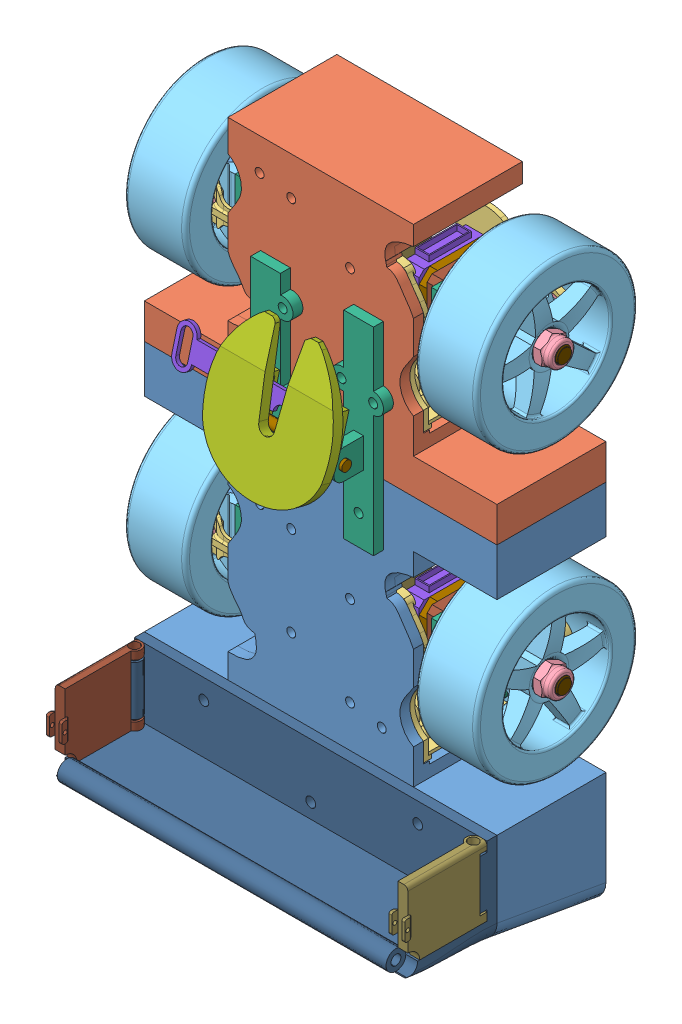
SolidWorks assembly Chassis assembly 2 - kopie, configuration Default. Lengths in mm.
Overall size (185.37 311.7 137.75).
160 component instances, 31 part files, 29 mates.
Components (placement in the parent):
- Dolly chassis half 1-1: Dolly chassis half 1 [Default] at (2.6348 264.5467 189.9496) size (178 185.23 55)
- Dolly chassis half 2-1: Dolly chassis half 2 [Default] at (2.6348 264.5467 189.9496) size (178 119.07 55)
- Module Assembly-1: Module Assembly [Default] at (-63.8652 93.3967 162.4496) x (0 -1 0) z (-1 0 0) size (68.25 51.28 97.81)
  - Housing-1: Housing [Default] at origin size (64.25 48.5 67.91)
  - Bearing 12x8-1: Bearing 12x8 [Default] at (0 -18.25 0.75) x (-0.914388 0 0.40484) z (-0.40484 0 -0.914388) size (12 3.5 12)
  - Spindle-1: Spindle [Default] at (0 2 0.75) size (49.04 45 20.5)
  - Spindle base-1: Spindle base [Default] at (0 2 -15.25) x (-1 0 0) z (0 -1 0) size (37.62 3.5 44.8)
  - Encoder-1: Encoder [Défaut] at (0 2 -12.48) x (0 1 0) z (0 0 1) size (28.68 37.25 10.4)
  - Wheel-1: Wheel [Default] at (0 2 -8.55) x (0.929787 0.368098 0) z (0.368098 -0.929787 0) size (81.5 31 81.5) (hidden)
  - Stepper Nema14-1: Stepper Nema14 [Predeterminado] at (4.764 -15.5 -30.1157) x (-1 0 0) z (0 1 0) size (37.8 40 35)
    - nema14_base-1: nema14_base [Predeterminado] at (-12.736 -8.6343 35) size (37.8 9 35)
    - nema14_centro-1: nema14_centro [Predeterminado] at (-12.736 0.3657 35) size (35 4 35)
    - nema14_eje-1: nema14_eje [Predeterminado] at (4.764 -6.6343 17.5) x (0 1 0) z (-0.939004 0 0.343907) size (38 5 5)
    - nema14_techo-1: nema14_techo [Predeterminado] at (-12.736 4.3657 35) size (35 9 35)
  - Servo motor-1: Servo motor [Default] at (-25.7048 26.288 -66.0832) x (0 0 1) z (1 0 0) size (11.5 29.2 32.5) (flexible)
    - TowerPro-SG90-Body-1: TowerPro-SG90-Body [Default] at (13.6721 7.288 30.7048) size (11.5 26 32.5)
    - ServoFinalGear-1: ServoFinalGear [Default] at (13.6721 33.288 25.7048) x (0.607544 0 -0.794286) z (0.794286 0 0.607544) size (4.64 3.2 4.64)
  - Control arm-1: Control arm [Default] at (0 -7.5 -52.4111) x (0.891007 0 0.45399) z (0.45399 0 -0.891007) size (37.9 4.5 7.8)
  - Ball joint assy-1: Ball joint assy [Default] at (-26.7302 -5 -12.8697) x (-0.874356 0 0.485286) z (0.485286 0 0.874356) size (15.43 16.21 22.24) (flexible)
    - Ball-1: Ball [Default] at origin size (5.5 15.11 5.5)
    - Joint-1: Joint [Default] at (-3.8823 13.66 -6.9948) x (0.874356 0 -0.485286) z (0 -1 0) size (5.1 22.6 5.1)
  - Ball joint assy-2: Ball joint assy [Default] at (-26.7302 -5 -66.0308) x (-0.846813 0 0.531891) z (0.531891 0 0.846813) size (16.34 16.21 21.85) (flexible)
    - Ball-1: Ball [Default] at origin size (5.5 15.11 5.5)
    - Joint-1: Joint [Default] at (4.2551 13.66 6.7745) x (-0.846813 0 0.531891) z (0 -1 0) size (5.1 22.6 5.1)
  - Steering rod-1: Steering rod [Default] at (-26.7302 -18.66 -18.4608) x (-0.014502 0.999895 0) z (-0.999895 -0.014502 0) size (3 28.27 3)
  - Wheel adapter-1: Wheel adapter [Default] at (0 2 -13.8175) x (0.291296 -0.956633 0) z (-0.956633 -0.291296 0) size (8.34 40 8.37)
  - Wheel spacer-1: Wheel spacer [Default] at (0 2 12.25) x (0.368098 -0.929787 0) z (0.929787 0.368098 0) size (13.86 8 12)
  - M3x5 din 7984-1: M3x5 din 7984 [Default] at (15.31 20.9 -16.25) x (0.933505 0.358563 0) z (0 0 -1) size (5.5 5.5 7)
  - Housing lid-1: Housing lid [Default] at (0 4 0) x (-1 0 0) z (0 0 1) size (68.25 9.28 69.91)
  - Bearing 12x8-3: Bearing 12x8 [Default] at (0 22.25 0.75) x (-0.914388 0 0.40484) z (0.40484 0 0.914388) size (12 3.5 12)
  - M8 nut-1: M8 nut [Default] at (0 2 16.6825) x (-0.817347 -0.576146 0) z (0 0 1) size (13 16.06 8.5)
  - M3x5 din 7984-2: M3x5 din 7984 [Default] at (15.31 -16.9 -16.25) x (-0.933505 0.358563 0) z (0 0 -1) size (5.5 5.5 7)
  - M3x5 din 7984-3: M3x5 din 7984 [Default] at (-15.31 20.9 -16.25) x (0.933505 -0.358563 0) z (0 0 -1) size (5.5 5.5 7)
  - M3x5 din 7984-4: M3x5 din 7984 [Default] at (-15.31 -16.9 -16.25) x (-0.933505 -0.358563 0) z (0 0 -1) size (5.5 5.5 7)
  - M3x5 din 7984-5: M3x5 din 7984 [Default] at (-13 15 -17.75) x (0.999849 0.017374 0) z (0 0 1) size (5.5 5.5 7)
  - M3x5 din 7984-6: M3x5 din 7984 [Default] at (-13 -11 -17.75) x (-0.999849 0.017374 0) z (0 0 1) size (5.5 5.5 7)
  - M3x5 din 7984-7: M3x5 din 7984 [Default] at (13 15 -17.75) x (0.999849 -0.017374 0) z (0 0 1) size (5.5 5.5 7)
  - M3x5 din 7984-8: M3x5 din 7984 [Default] at (13 -11 -17.75) x (-0.999849 -0.017374 0) z (0 0 1) size (5.5 5.5 7)
- Module Assembly-2: Module Assembly [Default] at (69.1348 93.3967 162.4496) x (0 1 0) z (1 0 0) size (68.25 51.28 97.81)
  - Housing-1: Housing [Default] at origin size (64.25 48.5 67.91)
  - Bearing 12x8-1: Bearing 12x8 [Default] at (0 -18.25 0.75) x (-0.914388 0 0.40484) z (-0.40484 0 -0.914388) size (12 3.5 12)
  - Spindle-1: Spindle [Default] at (0 2 0.75) size (49.04 45 20.5)
  - Spindle base-1: Spindle base [Default] at (0 2 -15.25) x (-1 0 0) z (0 -1 0) size (37.62 3.5 44.8)
  - Encoder-1: Encoder [Défaut] at (0 2 -12.48) x (0 1 0) z (0 0 1) size (28.68 37.25 10.4)
  - Wheel-1: Wheel [Default] at (0 2 -8.55) x (0.929787 0.368098 0) z (0.368098 -0.929787 0) size (81.5 31 81.5) (hidden)
  - Stepper Nema14-1: Stepper Nema14 [Predeterminado] at (4.764 -15.5 -30.1157) x (-1 0 0) z (0 1 0) size (37.8 40 35)
    - nema14_base-1: nema14_base [Predeterminado] at (-12.736 -8.6343 35) size (37.8 9 35)
    - nema14_centro-1: nema14_centro [Predeterminado] at (-12.736 0.3657 35) size (35 4 35)
    - nema14_eje-1: nema14_eje [Predeterminado] at (4.764 -6.6343 17.5) x (0 1 0) z (-0.939004 0 0.343907) size (38 5 5)
    - nema14_techo-1: nema14_techo [Predeterminado] at (-12.736 4.3657 35) size (35 9 35)
  - Servo motor-1: Servo motor [Default] at (-25.7048 26.288 -66.0832) x (0 0 1) z (1 0 0) size (11.5 29.2 32.5) (flexible)
    - TowerPro-SG90-Body-1: TowerPro-SG90-Body [Default] at (13.6721 7.288 30.7048) size (11.5 26 32.5)
    - ServoFinalGear-1: ServoFinalGear [Default] at (13.6721 33.288 25.7048) x (0.607544 0 -0.794286) z (0.794286 0 0.607544) size (4.64 3.2 4.64)
  - Control arm-1: Control arm [Default] at (0 -7.5 -52.4111) x (0.891007 0 0.45399) z (0.45399 0 -0.891007) size (37.9 4.5 7.8)
  - Ball joint assy-1: Ball joint assy [Default] at (-26.7302 -5 -12.8697) x (-0.874356 0 0.485286) z (0.485286 0 0.874356) size (15.43 16.21 22.24) (flexible)
    - Ball-1: Ball [Default] at origin size (5.5 15.11 5.5)
    - Joint-1: Joint [Default] at (-3.8823 13.66 -6.9948) x (0.874356 0 -0.485286) z (0 -1 0) size (5.1 22.6 5.1)
  - Ball joint assy-2: Ball joint assy [Default] at (-26.7302 -5 -66.0308) x (-0.846813 0 0.531891) z (0.531891 0 0.846813) size (16.34 16.21 21.85) (flexible)
    - Ball-1: Ball [Default] at origin size (5.5 15.11 5.5)
    - Joint-1: Joint [Default] at (4.2551 13.66 6.7745) x (-0.846813 0 0.531891) z (0 -1 0) size (5.1 22.6 5.1)
  - Steering rod-1: Steering rod [Default] at (-26.7302 -18.66 -18.4608) x (-0.014502 0.999895 0) z (-0.999895 -0.014502 0) size (3 28.27 3)
  - Wheel adapter-1: Wheel adapter [Default] at (0 2 -13.8175) x (0.291296 -0.956633 0) z (-0.956633 -0.291296 0) size (8.34 40 8.37)
  - Wheel spacer-1: Wheel spacer [Default] at (0 2 12.25) x (0.368098 -0.929787 0) z (0.929787 0.368098 0) size (13.86 8 12)
  - M3x5 din 7984-1: M3x5 din 7984 [Default] at (15.31 20.9 -16.25) x (0.933505 0.358563 0) z (0 0 -1) size (5.5 5.5 7)
  - Housing lid-1: Housing lid [Default] at (0 4 0) x (-1 0 0) z (0 0 1) size (68.25 9.28 69.91)
  - Bearing 12x8-3: Bearing 12x8 [Default] at (0 22.25 0.75) x (-0.914388 0 0.40484) z (0.40484 0 0.914388) size (12 3.5 12)
  - M8 nut-1: M8 nut [Default] at (0 2 16.6825) x (-0.817347 -0.576146 0) z (0 0 1) size (13 16.06 8.5)
  - M3x5 din 7984-2: M3x5 din 7984 [Default] at (15.31 -16.9 -16.25) x (-0.933505 0.358563 0) z (0 0 -1) size (5.5 5.5 7)
  - M3x5 din 7984-3: M3x5 din 7984 [Default] at (-15.31 20.9 -16.25) x (0.933505 -0.358563 0) z (0 0 -1) size (5.5 5.5 7)
  - M3x5 din 7984-4: M3x5 din 7984 [Default] at (-15.31 -16.9 -16.25) x (-0.933505 -0.358563 0) z (0 0 -1) size (5.5 5.5 7)
  - M3x5 din 7984-5: M3x5 din 7984 [Default] at (-13 15 -17.75) x (0.999849 0.017374 0) z (0 0 1) size (5.5 5.5 7)
  - M3x5 din 7984-6: M3x5 din 7984 [Default] at (-13 -11 -17.75) x (-0.999849 0.017374 0) z (0 0 1) size (5.5 5.5 7)
  - M3x5 din 7984-7: M3x5 din 7984 [Default] at (13 15 -17.75) x (0.999849 -0.017374 0) z (0 0 1) size (5.5 5.5 7)
  - M3x5 din 7984-8: M3x5 din 7984 [Default] at (13 -11 -17.75) x (-0.999849 -0.017374 0) z (0 0 1) size (5.5 5.5 7)
- Module Assembly-3: Module Assembly [Default] at (69.1348 238.0467 162.4496) x (0 1 0) z (1 0 0) size (68.25 51.28 97.81)
  - Housing-1: Housing [Default] at origin size (64.25 48.5 67.91)
  - Bearing 12x8-1: Bearing 12x8 [Default] at (0 -18.25 0.75) x (-0.914388 0 0.40484) z (-0.40484 0 -0.914388) size (12 3.5 12)
  - Spindle-1: Spindle [Default] at (0 2 0.75) size (49.04 45 20.5)
  - Spindle base-1: Spindle base [Default] at (0 2 -15.25) x (-1 0 0) z (0 -1 0) size (37.62 3.5 44.8)
  - Encoder-1: Encoder [Défaut] at (0 2 -12.48) x (0 1 0) z (0 0 1) size (28.68 37.25 10.4)
  - Wheel-1: Wheel [Default] at (0 2 -8.55) x (0.929787 0.368098 0) z (0.368098 -0.929787 0) size (81.5 31 81.5) (hidden)
  - Stepper Nema14-1: Stepper Nema14 [Predeterminado] at (4.764 -15.5 -30.1157) x (-1 0 0) z (0 1 0) size (37.8 40 35)
    - nema14_base-1: nema14_base [Predeterminado] at (-12.736 -8.6343 35) size (37.8 9 35)
    - nema14_centro-1: nema14_centro [Predeterminado] at (-12.736 0.3657 35) size (35 4 35)
    - nema14_eje-1: nema14_eje [Predeterminado] at (4.764 -6.6343 17.5) x (0 1 0) z (-0.939004 0 0.343907) size (38 5 5)
    - nema14_techo-1: nema14_techo [Predeterminado] at (-12.736 4.3657 35) size (35 9 35)
  - Servo motor-1: Servo motor [Default] at (-25.7048 26.288 -66.0832) x (0 0 1) z (1 0 0) size (11.5 29.2 32.5) (flexible)
    - TowerPro-SG90-Body-1: TowerPro-SG90-Body [Default] at (13.6721 7.288 30.7048) size (11.5 26 32.5)
    - ServoFinalGear-1: ServoFinalGear [Default] at (13.6721 33.288 25.7048) x (0.607544 0 -0.794286) z (0.794286 0 0.607544) size (4.64 3.2 4.64)
  - Control arm-1: Control arm [Default] at (0 -7.5 -52.4111) x (0.891007 0 0.45399) z (0.45399 0 -0.891007) size (37.9 4.5 7.8)
  - Ball joint assy-1: Ball joint assy [Default] at (-26.7302 -5 -12.8697) x (-0.874356 0 0.485286) z (0.485286 0 0.874356) size (15.43 16.21 22.24) (flexible)
    - Ball-1: Ball [Default] at origin size (5.5 15.11 5.5)
    - Joint-1: Joint [Default] at (-3.8823 13.66 -6.9948) x (0.874356 0 -0.485286) z (0 -1 0) size (5.1 22.6 5.1)
  - Ball joint assy-2: Ball joint assy [Default] at (-26.7302 -5 -66.0308) x (-0.846813 0 0.531891) z (0.531891 0 0.846813) size (16.34 16.21 21.85) (flexible)
    - Ball-1: Ball [Default] at origin size (5.5 15.11 5.5)
    - Joint-1: Joint [Default] at (4.2551 13.66 6.7745) x (-0.846813 0 0.531891) z (0 -1 0) size (5.1 22.6 5.1)
  - Steering rod-1: Steering rod [Default] at (-26.7302 -18.66 -18.4608) x (-0.014502 0.999895 0) z (-0.999895 -0.014502 0) size (3 28.27 3)
  - Wheel adapter-1: Wheel adapter [Default] at (0 2 -13.8175) x (0.291296 -0.956633 0) z (-0.956633 -0.291296 0) size (8.34 40 8.37)
  - Wheel spacer-1: Wheel spacer [Default] at (0 2 12.25) x (0.368098 -0.929787 0) z (0.929787 0.368098 0) size (13.86 8 12)
  - M3x5 din 7984-1: M3x5 din 7984 [Default] at (15.31 20.9 -16.25) x (0.933505 0.358563 0) z (0 0 -1) size (5.5 5.5 7)
  - Housing lid-1: Housing lid [Default] at (0 4 0) x (-1 0 0) z (0 0 1) size (68.25 9.28 69.91)
  - Bearing 12x8-3: Bearing 12x8 [Default] at (0 22.25 0.75) x (-0.914388 0 0.40484) z (0.40484 0 0.914388) size (12 3.5 12)
  - M8 nut-1: M8 nut [Default] at (0 2 16.6825) x (-0.817347 -0.576146 0) z (0 0 1) size (13 16.06 8.5)
  - M3x5 din 7984-2: M3x5 din 7984 [Default] at (15.31 -16.9 -16.25) x (-0.933505 0.358563 0) z (0 0 -1) size (5.5 5.5 7)
  - M3x5 din 7984-3: M3x5 din 7984 [Default] at (-15.31 20.9 -16.25) x (0.933505 -0.358563 0) z (0 0 -1) size (5.5 5.5 7)
  - M3x5 din 7984-4: M3x5 din 7984 [Default] at (-15.31 -16.9 -16.25) x (-0.933505 -0.358563 0) z (0 0 -1) size (5.5 5.5 7)
  - M3x5 din 7984-5: M3x5 din 7984 [Default] at (-13 15 -17.75) x (0.999849 0.017374 0) z (0 0 1) size (5.5 5.5 7)
  - M3x5 din 7984-6: M3x5 din 7984 [Default] at (-13 -11 -17.75) x (-0.999849 0.017374 0) z (0 0 1) size (5.5 5.5 7)
  - M3x5 din 7984-7: M3x5 din 7984 [Default] at (13 15 -17.75) x (0.999849 -0.017374 0) z (0 0 1) size (5.5 5.5 7)
  - M3x5 din 7984-8: M3x5 din 7984 [Default] at (13 -11 -17.75) x (-0.999849 -0.017374 0) z (0 0 1) size (5.5 5.5 7)
- Module Assembly-4: Module Assembly [Default] at (-63.8652 238.0467 162.4496) x (0 -1 0) z (-1 0 0) size (68.25 51.28 97.81)
  - Housing-1: Housing [Default] at origin size (64.25 48.5 67.91)
  - Bearing 12x8-1: Bearing 12x8 [Default] at (0 -18.25 0.75) x (-0.914388 0 0.40484) z (-0.40484 0 -0.914388) size (12 3.5 12)
  - Spindle-1: Spindle [Default] at (0 2 0.75) size (49.04 45 20.5)
  - Spindle base-1: Spindle base [Default] at (0 2 -15.25) x (-1 0 0) z (0 -1 0) size (37.62 3.5 44.8)
  - Encoder-1: Encoder [Défaut] at (0 2 -12.48) x (0 1 0) z (0 0 1) size (28.68 37.25 10.4)
  - Wheel-1: Wheel [Default] at (0 2 -8.55) x (0.929787 0.368098 0) z (0.368098 -0.929787 0) size (81.5 31 81.5) (hidden)
  - Stepper Nema14-1: Stepper Nema14 [Predeterminado] at (4.764 -15.5 -30.1157) x (-1 0 0) z (0 1 0) size (37.8 40 35)
    - nema14_base-1: nema14_base [Predeterminado] at (-12.736 -8.6343 35) size (37.8 9 35)
    - nema14_centro-1: nema14_centro [Predeterminado] at (-12.736 0.3657 35) size (35 4 35)
    - nema14_eje-1: nema14_eje [Predeterminado] at (4.764 -6.6343 17.5) x (0 1 0) z (-0.939004 0 0.343907) size (38 5 5)
    - nema14_techo-1: nema14_techo [Predeterminado] at (-12.736 4.3657 35) size (35 9 35)
  - Servo motor-1: Servo motor [Default] at (-25.7048 26.288 -66.0832) x (0 0 1) z (1 0 0) size (11.5 29.2 32.5) (flexible)
    - TowerPro-SG90-Body-1: TowerPro-SG90-Body [Default] at (13.6721 7.288 30.7048) size (11.5 26 32.5)
    - ServoFinalGear-1: ServoFinalGear [Default] at (13.6721 33.288 25.7048) x (0.607544 0 -0.794286) z (0.794286 0 0.607544) size (4.64 3.2 4.64)
  - Control arm-1: Control arm [Default] at (0 -7.5 -52.4111) x (0.891007 0 0.45399) z (0.45399 0 -0.891007) size (37.9 4.5 7.8)
  - Ball joint assy-1: Ball joint assy [Default] at (-26.7302 -5 -12.8697) x (-0.874356 0 0.485286) z (0.485286 0 0.874356) size (15.43 16.21 22.24) (flexible)
    - Ball-1: Ball [Default] at origin size (5.5 15.11 5.5)
    - Joint-1: Joint [Default] at (-3.8823 13.66 -6.9948) x (0.874356 0 -0.485286) z (0 -1 0) size (5.1 22.6 5.1)
  - Ball joint assy-2: Ball joint assy [Default] at (-26.7302 -5 -66.0308) x (-0.846813 0 0.531891) z (0.531891 0 0.846813) size (16.34 16.21 21.85) (flexible)
    - Ball-1: Ball [Default] at origin size (5.5 15.11 5.5)
    - Joint-1: Joint [Default] at (4.2551 13.66 6.7745) x (-0.846813 0 0.531891) z (0 -1 0) size (5.1 22.6 5.1)
  - Steering rod-1: Steering rod [Default] at (-26.7302 -18.66 -18.4608) x (-0.014502 0.999895 0) z (-0.999895 -0.014502 0) size (3 28.27 3)
  - Wheel adapter-1: Wheel adapter [Default] at (0 2 -13.8175) x (0.291296 -0.956633 0) z (-0.956633 -0.291296 0) size (8.34 40 8.37)
  - Wheel spacer-1: Wheel spacer [Default] at (0 2 12.25) x (0.368098 -0.929787 0) z (0.929787 0.368098 0) size (13.86 8 12)
  - M3x5 din 7984-1: M3x5 din 7984 [Default] at (15.31 20.9 -16.25) x (0.933505 0.358563 0) z (0 0 -1) size (5.5 5.5 7)
  - Housing lid-1: Housing lid [Default] at (0 4 0) x (-1 0 0) z (0 0 1) size (68.25 9.28 69.91)
  - Bearing 12x8-3: Bearing 12x8 [Default] at (0 22.25 0.75) x (-0.914388 0 0.40484) z (0.40484 0 0.914388) size (12 3.5 12)
  - M8 nut-1: M8 nut [Default] at (0 2 16.6825) x (-0.817347 -0.576146 0) z (0 0 1) size (13 16.06 8.5)
  - M3x5 din 7984-2: M3x5 din 7984 [Default] at (15.31 -16.9 -16.25) x (-0.933505 0.358563 0) z (0 0 -1) size (5.5 5.5 7)
  - M3x5 din 7984-3: M3x5 din 7984 [Default] at (-15.31 20.9 -16.25) x (0.933505 -0.358563 0) z (0 0 -1) size (5.5 5.5 7)
  - M3x5 din 7984-4: M3x5 din 7984 [Default] at (-15.31 -16.9 -16.25) x (-0.933505 -0.358563 0) z (0 0 -1) size (5.5 5.5 7)
  - M3x5 din 7984-5: M3x5 din 7984 [Default] at (-13 15 -17.75) x (0.999849 0.017374 0) z (0 0 1) size (5.5 5.5 7)
  - M3x5 din 7984-6: M3x5 din 7984 [Default] at (-13 -11 -17.75) x (-0.999849 0.017374 0) z (0 0 1) size (5.5 5.5 7)
  - M3x5 din 7984-7: M3x5 din 7984 [Default] at (13 15 -17.75) x (0.999849 -0.017374 0) z (0 0 1) size (5.5 5.5 7)
  - M3x5 din 7984-8: M3x5 din 7984 [Default] at (13 -11 -17.75) x (-0.999849 -0.017374 0) z (0 0 1) size (5.5 5.5 7)
- Wheel-1: Wheel [Default] at (60.5848 93.3967 164.4496) x (0 0.146111 0.989268) z (0 0.989268 -0.146111) size (81.5 31 81.5)
- Wheel-2: Wheel [Default] at (60.5848 238.0467 164.4496) x (0 0.783676 -0.62117) z (0 -0.62117 -0.783676) size (81.5 31 81.5)
- Wheel-3: Wheel [Default] at (-55.3152 238.0467 164.4496) x (0 -0.929787 0.368098) z (0 -0.368098 -0.929787) size (81.5 31 81.5)
- Wheel-4: Wheel [Default] at (-55.3152 93.3967 164.4496) x (0 -0.783676 -0.62117) z (0 0.62117 -0.783676) size (81.5 31 81.5)
- Fifth_wheel_assembly-1: Fifth_wheel_assembly [Default] at (27.3821 135.1631 149.1448) x (-1 0 0) z (0 1 0) size (90.59 41.74 100)
  - Fifth_wheel_mount-1: Fifth_wheel_mount [Default] at (-6.9031 48.3048 102.7348) size (67.09 20 100)
  - Fifth_wheel_disk-1: Fifth_wheel_disk [Default] at (-5.9031 71.3457 44.4932) x (1 0 0) z (0 -0.255937 0.966694) size (66.74 23.06 75.99)
  - Fifth_wheel_kingpin-1: Fifth_wheel_kingpin [Default] at (-1.4031 62.5809 65.8769) x (1 0 0) z (0 -0.255937 0.966694) size (80 2 20)
  - Fifth_wheel_axle-1: Fifth_wheel_axle [Default] at (51.5969 60.8048 45.2348) x (0 0.948415 -0.31703) z (1 0 0) size (5 5 55)
- front assembly 2-1: front assembly 2 [Default] at (-66.6852 152.8407 117.1017) x (1 0 0) z (0 -1 0) size (181 187.95 83.28)
  - Foldable front base 2-1: Foldable front base 2 [Default] at (158.3211 77.8479 159.546) size (179.15 52.01 49.18)
  - foldable front flap 2-1: foldable front flap 2 [Default] at (69.3211 122.8479 151.0232) x (-1 0 0) z (0 0 -1) size (178.61 145.94 74.18) (hidden)
  - Foldable front side flap right 2-1: Foldable front side flap right 2 [Default] at (-17.1789 86.3479 110.946) x (0 0 1) z (-1 0 0) size (35 43 8.5)
  - Foldable front side flap left 2-1: Foldable front side flap left 2 [Default] at (155.8211 86.3479 145.946) x (0 0 -1) z (1 0 0) size (35 43 8.5)
Mates (geometry in assembly coordinates):
- Coincident1: coincident: plane of Dolly chassis half 1-1 through (-44.2041 168.828 -11.5535) normal (0 1 0); plane of Dolly chassis half 2-1 through (-44.2041 168.828 -67.8767) normal (0 -1 0)
- Coincident2: coincident: plane of Dolly chassis half 1-1 through (2.6348 264.5467 194.9496) normal (0 0 1); plane of Dolly chassis half 2-1 through (2.6348 264.5467 194.9496) normal (0 0 1)
- Coincident3: coincident: plane of Dolly chassis half 1-1 through (49.4737 264.5467 194.9496) normal (1 0 0); plane of Dolly chassis half 2-1 through (49.4737 264.5467 194.9496) normal (1 0 0)
- Coincident4: coincident: plane of Dolly chassis half 1-1 through (2.6348 264.5467 189.9496) normal (0 0 -1); plane of Module Assembly-1/Housing lid-1 through (-63.8652 93.3967 189.9496) normal (0 0 1)
- Coincident5: coincident: plane of Dolly chassis half 1-1 through (-44.2041 264.5467 194.9496) normal (-1 0 0); plane of Module Assembly-1/Housing lid-1 through (-44.2041 93.3967 187.4496) normal (-1 0 0)
- Coincident6: coincident: plane of Dolly chassis half 1-1 through (49.4737 119.8967 194.9496) normal (1 0 0); plane of Module Assembly-2/Housing lid-1 through (49.4737 93.3967 187.4496) normal (1 0 0)
- Coincident7: coincident: plane of Dolly chassis half 1-1 through (2.6348 264.5467 189.9496) normal (0 0 -1); plane of Module Assembly-2/Housing lid-1 through (69.1348 93.3967 189.9496) normal (0 0 1)
- Coincident8: coincident: plane of Dolly chassis half 2-1 through (2.6348 264.5467 189.9496) normal (0 0 -1); plane of Module Assembly-3/Housing lid-1 through (69.1348 238.0467 189.9496) normal (0 0 1)
- Coincident9: coincident: plane of Dolly chassis half 2-1 through (49.4737 264.5467 194.9496) normal (1 0 0); plane of Module Assembly-3/Housing lid-1 through (49.4737 238.0467 187.4496) normal (1 0 0)
- Coincident10: coincident: plane of Dolly chassis half 2-1 through (-44.2041 264.5467 194.9496) normal (-1 0 0); plane of Module Assembly-4/Housing lid-1 through (-44.2041 238.0467 187.4496) normal (-1 0 0)
- Coincident11: coincident: plane of Dolly chassis half 1-1 through (2.6348 264.5467 189.9496) normal (0 0 -1); plane of Module Assembly-4/Housing lid-1 through (-63.8652 238.0467 189.9496) normal (0 0 1)
- Concentric5: concentric: cylinder of Module Assembly-2/Wheel adapter-1 through (55.3173 93.3967 164.4496) axis (-1 0 0) radius 4; cylinder of Wheel-1 through (60.5848 93.3967 164.4496) axis (1 0 0) radius 4
- Coincident15: coincident: plane of Module Assembly-2/Wheel spacer-1 through (73.3848 90.8464 170.8913) normal (0 0.146111 0.989268); plane of Wheel-1 through (81.3848 90.8464 170.8913) normal (0 -0.146111 -0.989268)
- Coincident16: coincident: plane of Module Assembly-2/Wheel spacer-1 through (81.3848 93.3967 164.4496) normal (1 0 0); plane of Wheel-1 through (81.3848 93.3967 164.4496) normal (-1 0 0)
- Concentric6: concentric: cylinder of Module Assembly-3/Wheel adapter-1 through (55.3173 238.0467 164.4496) axis (-1 0 0) radius 4; cylinder of Wheel-2 through (60.5848 238.0467 164.4496) axis (1 0 0) radius 4
- Coincident17: coincident: plane of Module Assembly-3/Wheel spacer-1 through (73.3848 235.4964 170.8913) normal (0 0.146111 0.989268); plane of Wheel-2 through (81.3848 235.4964 170.8913) normal (0 -0.146111 -0.989268)
- Coincident18: coincident: plane of Module Assembly-3/Wheel spacer-1 through (81.3848 238.0467 164.4496) normal (1 0 0); plane of Wheel-2 through (81.3848 238.0467 164.4496) normal (-1 0 0)
- Concentric7: concentric: cylinder of Module Assembly-4/Wheel adapter-1 through (-50.0477 238.0467 164.4496) axis (1 0 0) radius 4; cylinder of Wheel-3 through (-55.3152 238.0467 164.4496) axis (-1 0 0) radius 4
- Coincident19: coincident: plane of Module Assembly-4/Wheel spacer-1 through (-68.1152 240.5969 170.8913) normal (0 -0.146111 0.989268); plane of Wheel-3 through (-76.1152 240.5969 170.8913) normal (0 0.146111 -0.989268)
- Coincident20: coincident: plane of Module Assembly-4/Wheel spacer-1 through (-76.1152 238.0467 164.4496) normal (-1 0 0); plane of Wheel-3 through (-76.1152 238.0467 164.4496) normal (1 0 0)
- Concentric8: concentric: cylinder of Module Assembly-1/Wheel adapter-1 through (-50.0477 93.3967 164.4496) axis (1 0 0) radius 4; cylinder of Wheel-4 through (-55.3152 93.3967 164.4496) axis (-1 0 0) radius 4
- Coincident21: coincident: plane of Module Assembly-1/Wheel spacer-1 through (-68.1152 95.9469 170.8913) normal (0 -0.146111 0.989268); plane of Wheel-4 through (-76.1152 95.9469 170.8913) normal (0 0.146111 -0.989268)
- Coincident22: coincident: plane of Module Assembly-1/Wheel spacer-1 through (-76.1152 93.3967 164.4496) normal (-1 0 0); plane of Wheel-4 through (-76.1152 93.3967 164.4496) normal (1 0 0)
- Coincident23: coincident: plane of Dolly chassis half 2-1 through (2.6348 264.5467 194.9496) normal (0 0 1); plane of Fifth_wheel_assembly-1/Fifth_wheel_mount-1 through (34.2852 237.898 194.9496) normal (0 0 -1)
- Parallel2: parallel: plane of Dolly chassis half 2-1 through (2.6348 287.898 189.9496) normal (0 1 0); plane of Fifth_wheel_assembly-1/Fifth_wheel_mount-1 through (34.2852 237.898 199.9496) normal (0 1 0)
- Distance1: distance = 50 mm: plane of Fifth_wheel_assembly-1/Fifth_wheel_mount-1 through (34.2852 237.898 199.9496) normal (0 1 0); plane of Dolly chassis half 2-1 through (2.6348 287.898 189.9496) normal (0 1 0)
- Coincident24: coincident: plane of Dolly chassis half 1-1 through (2.6348 264.5467 194.9496) normal (0 0 1); plane of front assembly 2-1/Foldable front base 2-1 through (91.6359 -6.7054 194.9496) normal (0 0 -1)
- Coincident25: coincident: plane of Dolly chassis half 1-1 through (147.4822 -16.4033 139.9496) normal (0 -0.984808 0.173648); plane of front assembly 2-1/Foldable front base 2-1 through (91.6359 -6.7054 194.9496) normal (0 -0.984808 0.173648)
- Coincident26: coincident: plane of Dolly chassis half 1-1 through (-86.3641 264.5467 189.9496) normal (-1 0 0); plane of front assembly 2-1/Foldable front base 2-1 through (-86.3641 -6.7054 239.9496) normal (-1 0 0)
